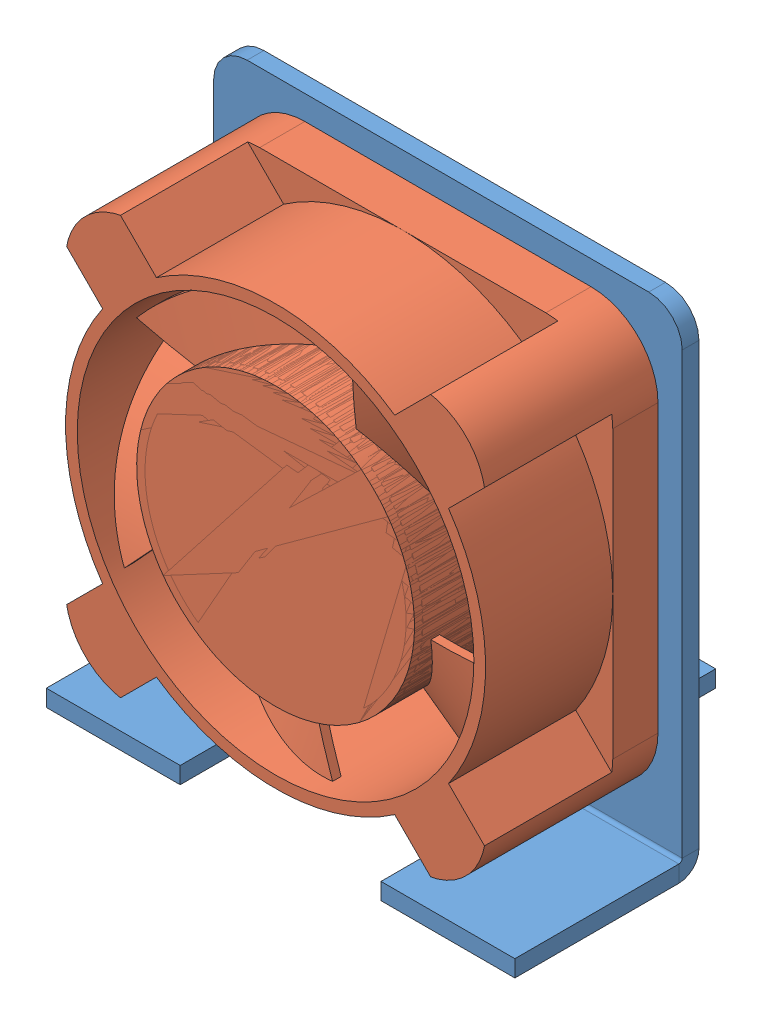
SolidWorks assembly Halterung-Lüfter, configuration Standard. Lengths in mm.
Overall size (28 29.5 21.44).
2 component instances, 2 part files, 6 mates.
Components (placement in the parent):
- Halterung-Lüfter-1: Halterung-Lüfter [Standard] at origin size (28 29.5 21)
- Hobby King X-Car 60A Brushless Car ESC - Lüfter-1: Hobby King X-Car 60A Brushless Car ESC - Lüfter [Ohne Stecker] at (0 15.5 0) x (1 0 0) z (0 -1 0) size (25.1 10.44 25.1)
Mates (geometry in assembly coordinates):
- Deckungsgleich1: coincident aligned: plane of Halterung-Lüfter-1 through (0 0 0) normal (0 0 1); plane of assembly through (0 0 0) normal (0 0 1)
- Deckungsgleich2: coincident aligned: plane of Halterung-Lüfter-1 through (0 0 0) normal (1 0 0); plane of assembly through (0 0 0) normal (1 0 0)
- Deckungsgleich3: coincident aligned: plane of Halterung-Lüfter-1 through (0 0 0) normal (0 1 0); plane of assembly through (0 0 0) normal (0 1 0)
- Deckungsgleich4: coincident anti-aligned: plane of Halterung-Lüfter-1 through (0 0 0) normal (0 0 1); plane of Hobby King X-Car 60A Brushless Car ESC - Lüfter-1 through (0 15.5 0) normal (0 0 -1)
- Konzentrisch1: concentric: cylinder of Halterung-Lüfter-1 through (-10 25.5 -1) axis (0 0 1) radius 1.25; point of Hobby King X-Car 60A Brushless Car ESC - Lüfter-1
- Konzentrisch2: concentric: cylinder of Halterung-Lüfter-1 through (10 25.5 -1) axis (0 0 1) radius 1.25; point of Hobby King X-Car 60A Brushless Car ESC - Lüfter-1
